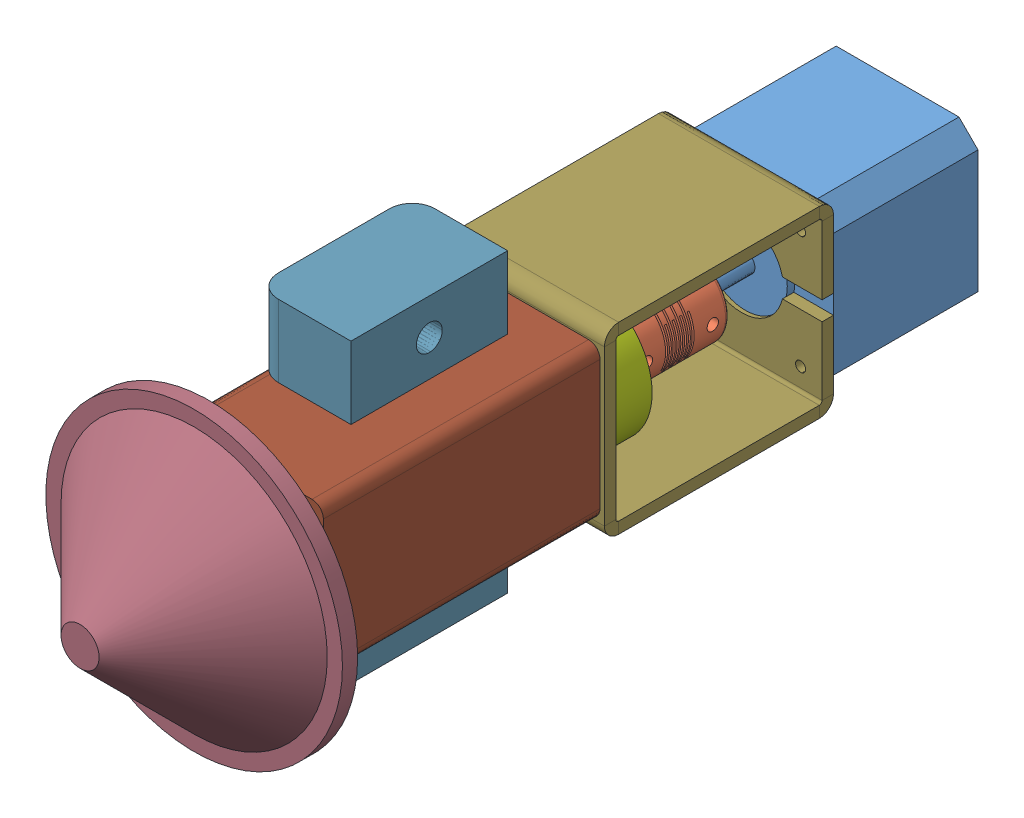
SolidWorks assembly ТП.SH21(K1).02.00 - Линейный движитель, configuration 00. Lengths in mm.
Overall size (78 78 215).
15 component instances, 14 part files, 41 mates.
Components (placement in the parent):
- 17HS4401 (Nema17)-1: 17HS4401 (Nema17) [--] at origin size (42.3 42.3 63.5)
- Муфта гибкая-1: Муфта гибкая [--] at (0 0 42.25) size (20 20 26)
- Винт CS М12х2х150-1: Винт CS М12х2х150 [--] at (0 0 133) x (0.999367 0.035585 0) z (0 0 1) size (12 12.62 100)
- ТП.SH21(K1).02.01 - Упор винта-1: ТП.SH21(K1).02.01 - Упор винта [--] at (0 0 57.25) size (14 14 13)
- Подшипник упорный 8100-1: Подшипник упорный 8100 [--] at (0 0 48.25) x (1 0 0) z (0 -1 0) size (24 9 24)
- Стопор внутренний до 165мм (ГОСТ 13943-86)-1: Стопор внутренний до 165мм (ГОСТ 13943-86) [Кольцо 24] at (0 0 47.05) size (25.5 26.7 1.2)
- ТП.SH21(K1).02.02 - Обойма под 8100-1: ТП.SH21(K1).02.02 - Обойма под 8100 [--] at (0 0 48.25) size (35 35 16.2)
- Гайка DCM12-1: Гайка DCM12 [Доработка] at (0 0 64.25) x (0 0 1) z (-0.707107 -0.707107 0) size (30.72 41.36 41.36)
- ТП.SH21(K1).02.03 - Профильная труба 35х35х2-1: ТП.SH21(K1).02.03 - Профильная труба 35х35х2 [--] at (0 0 74.25) size (35 35 68.75)
- ТП.SH21(K1).02.04 - Заглушка35х35-1: ТП.SH21(K1).02.04 - Заглушка35х35 [--] at (0 0 70.25) size (35 35 4)
- ТП.SH21(K1).02.05 - Профильная труба 40х40х2-1: ТП.SH21(K1).02.05 - Профильная труба 40х40х2 [--] at (0 0 60.25) size (40 40 72.75)
- ТП.SH21(K1).02.06 - Заглушка 40х40-1: ТП.SH21(K1).02.06 - Заглушка 40х40 [--] at (0 0 60.25) size (42.3 48.3 60.25)
- ТП.SH21(K1).02.07 - Уловитель-1: ТП.SH21(K1).02.07 - Уловитель [--] at (0 0 143) size (78 78 39)
- ТП.SH21(K1).02.08 - Фиксатор-1: ТП.SH21(K1).02.08 - Фиксатор [--] at (-20 -20 60.25) x (0 1 0) z (1 0 0) size (19 41.2 25.1)
- ТП.SH21(K1).02.08 - Фиксатор-2: ТП.SH21(K1).02.08 - Фиксатор [--] at (-20 39 60.25) x (0 1 0) z (1 0 0) size (19 41.2 25.1)
Mates (geometry in assembly coordinates):
- Концентричный1: concentric: cylinder of 17HS4401 (Nema17)-1 through (0 0 25.5) axis (0 0 -1) radius 2.5; cylinder of Муфта гибкая-1 through (0 0 33.9853) axis (0 0 -1) radius 3
- Совпадение1: coincident: plane of 17HS4401 (Nema17)-1 through (0 0 25.5) normal (0 0 1); plane of Муфта гибкая-1 through (-10 5 25.5) normal (0 0 1)
- Концентричный2: concentric: cylinder of 17HS4401 (Nema17)-1 through (0 0 25.5) axis (0 0 -1) radius 2.5; cylinder of Винт CS М12х2х150-1 through (0 0 33) axis (0 0 1) radius 6
- Совпадение2: coincident: plane of Муфта гибкая-1 through (-10 10 33) normal (0 0 -1); plane of Винт CS М12х2х150-1 through (0 0 33) normal (0 0 -1)
- Совпадение3: coincident: plane of ТП.SH21(K1).02.01 - Упор винта-1 through (0 0 57.25) normal (0 1 0); plane of assembly through (0 0 0) normal (0 1 0)
- Совпадение4: coincident: plane of ТП.SH21(K1).02.01 - Упор винта-1 through (0 0 57.25) normal (1 0 0); plane of assembly through (0 0 0) normal (1 0 0)
- Совпадение5: coincident: plane of ТП.SH21(K1).02.01 - Упор винта-1 through (0 0 57.25) normal (0 0 1); line of assembly
- Концентричный3: concentric: cylinder of Винт CS М12х2х150-1 through (0 0 992.25) axis (0 0 1) radius 2.9981; cylinder of Подшипник упорный 8100-1 through (0 0 -951.75) axis (0 0 -1) radius 5
- Совпадение6: coincident: plane of Подшипник упорный 8100-1 through (5.6 0 48.25) normal (0 0 -1); line of assembly
- Совпадение7: coincident: plane of Подшипник упорный 8100-1 through (5.6 0 48.25) normal (0 0 -1); plane of Стопор внутренний до 165мм (ГОСТ 13943-86)-1 through (-7.2178 -4.9058 48.25) normal (0 0 1)
- Концентричный4: concentric: cylinder of Подшипник упорный 8100-1 through (0 0 -951.75) axis (0 0 -1) radius 12; cylinder of Стопор внутренний до 165мм (ГОСТ 13943-86)-1 through (0 0 48.25) axis (0 0 -1) radius 12.75
- Совпадение8: coincident: point of Стопор внутренний до 165мм (ГОСТ 13943-86)-1; plane of assembly
- Совпадение9: coincident: plane of ТП.SH21(K1).02.02 - Обойма под 8100-1 through (0 0 48.25) normal (0 0 1); line of assembly
- Совпадение10: coincident: plane of ТП.SH21(K1).02.02 - Обойма под 8100-1 through (0 0 48.25) normal (0 1 0); plane of assembly through (0 0 0) normal (0 1 0)
- Совпадение11: coincident: plane of ТП.SH21(K1).02.02 - Обойма под 8100-1 through (0 0 48.25) normal (1 0 0); plane of assembly through (0 0 0) normal (1 0 0)
- Концентричный5: concentric: cylinder of Гайка DCM12-1 through (0 0 -239.9159) axis (0 0 -1) radius 11; cylinder of ТП.SH21(K1).02.02 - Обойма под 8100-1 through (0 0 1048.25) axis (0 0 1) radius 17.5
- Расстояние1: distance = 4 mm: plane of Гайка DCM12-1 through (-15.5563 15.5563 64.25) normal (0 0 -1); plane of ТП.SH21(K1).02.02 - Обойма под 8100-1 through (0 10 60.25) normal (0 0 1)
- Параллельность1: parallel: plane of 17HS4401 (Nema17)-1 through (-16.15 21.15 -38) normal (0 1 0); line of Гайка DCM12-1 through (10.9602 10.9602 64.25) axis (-1 0 0)
- Параллельность2: parallel: plane of Гайка DCM12-1 through (12.5 15.5 94.972) normal (0 1 0); plane of ТП.SH21(K1).02.03 - Профильная труба 35х35х2-1 through (14.5 17.5 192.4975) normal (0 1 0)
- Совпадение12: coincident: point of ТП.SH21(K1).02.03 - Профильная труба 35х35х2-1; line of assembly
- Параллельность3: parallel: plane of Гайка DCM12-1 through (-15.5 -12.5 94.972) normal (-1 0 0); plane of ТП.SH21(K1).02.03 - Профильная труба 35х35х2-1 through (-17.5 14.5 192.4975) normal (-1 0 0)
- Расстояние2: distance = 4 mm: plane of Гайка DCM12-1 through (-15.5563 15.5563 70.25) normal (0 0 1); plane of ТП.SH21(K1).02.03 - Профильная труба 35х35х2-1 through (-14.5 -14.5 74.25) normal (0 0 -1)
- Совпадение13: coincident: plane of Гайка DCM12-1 through (-15.5563 15.5563 70.25) normal (0 0 1); plane of ТП.SH21(K1).02.04 - Заглушка35х35-1 through (0 0 70.25) normal (0 0 1)
- Совпадение14: coincident: plane of ТП.SH21(K1).02.04 - Заглушка35х35-1 through (0 0 70.25) normal (0 1 0); plane of assembly through (0 0 0) normal (0 1 0)
- Совпадение15: coincident: plane of ТП.SH21(K1).02.04 - Заглушка35х35-1 through (0 0 70.25) normal (1 0 0); plane of assembly through (0 0 0) normal (1 0 0)
- Совпадение16: coincident: plane of ТП.SH21(K1).02.02 - Обойма под 8100-1 through (0 10 60.25) normal (0 0 1); plane of ТП.SH21(K1).02.05 - Профильная труба 40х40х2-1 through (-17 -17 60.25) normal (0 0 -1)
- Совпадение17: coincident: unknown of ?
- Параллельность4: parallel: plane of ТП.SH21(K1).02.03 - Профильная труба 35х35х2-1 through (17.5 14.5 192.4975) normal (1 0 0); plane of ТП.SH21(K1).02.05 - Профильная труба 40х40х2-1 through (20 17 189.5685) normal (1 0 0)
- Совпадение18: coincident: plane of ТП.SH21(K1).02.05 - Профильная труба 40х40х2-1 through (-17 -17 60.25) normal (0 0 -1); plane of ТП.SH21(K1).02.06 - Заглушка 40х40-1 through (0 0 60.25) normal (0 0 1)
- Совпадение19: coincident: plane of ТП.SH21(K1).02.06 - Заглушка 40х40-1 through (0 0 60.25) normal (0 1 0); plane of assembly through (0 0 0) normal (0 1 0)
- Совпадение20: coincident: plane of ТП.SH21(K1).02.06 - Заглушка 40х40-1 through (0 0 60.25) normal (1 0 0); plane of assembly through (0 0 0) normal (1 0 0)
- Совпадение21: coincident: plane of ТП.SH21(K1).02.03 - Профильная труба 35х35х2-1 through (0 0 143) normal (0 0 1); plane of ТП.SH21(K1).02.07 - Уловитель-1 through (0 0 143) normal (0 0 1)
- Совпадение22: coincident: plane of ТП.SH21(K1).02.07 - Уловитель-1 through (0 0 143) normal (0 1 0); line of assembly
- Совпадение23: coincident: plane of ТП.SH21(K1).02.07 - Уловитель-1 through (0 0 143) normal (1 0 0); line of assembly
- Параллельность5: parallel: plane of ТП.SH21(K1).02.03 - Профильная труба 35х35х2-1 through (14.5 17.5 192.4975) normal (0 1 0); plane of ТП.SH21(K1).02.07 - Уловитель-1 through (0 0 143) normal (0 1 0)
- Совпадение24: coincident: plane of ТП.SH21(K1).02.05 - Профильная труба 40х40х2-1 through (-20 17 189.5685) normal (-1 0 0); plane of ТП.SH21(K1).02.08 - Фиксатор-1 through (-20 -20 60.25) normal (1 0 0)
- Совпадение25: coincident: plane of ТП.SH21(K1).02.05 - Профильная труба 40х40х2-1 through (17 -20 189.5685) normal (0 -1 0); plane of ТП.SH21(K1).02.08 - Фиксатор-1 through (-20 -20 60.25) normal (0 1 0)
- Совпадение26: coincident: plane of ТП.SH21(K1).02.06 - Заглушка 40х40-1 through (98.3702 21.15 60.25) normal (0 0 1); plane of ТП.SH21(K1).02.08 - Фиксатор-1 through (-20 -20 60.25) normal (0 0 1)
- Совпадение27: coincident: plane of ТП.SH21(K1).02.05 - Профильная труба 40х40х2-1 through (17 20 189.5685) normal (0 1 0); plane of ТП.SH21(K1).02.08 - Фиксатор-2 through (477.4989 20 18) normal (0 -1 0)
- Совпадение28: coincident: plane of ТП.SH21(K1).02.08 - Фиксатор-1 through (5.1 -87.2437 110.85) normal (0 0 1); plane of ТП.SH21(K1).02.08 - Фиксатор-2 through (5.1 -28.2437 110.85) normal (0 0 1)
- Совпадение29: coincident: plane of ТП.SH21(K1).02.08 - Фиксатор-1 through (-20 -87.2437 104.85) normal (-1 0 0); plane of ТП.SH21(K1).02.08 - Фиксатор-2 through (-20 -28.2437 104.85) normal (-1 0 0)
